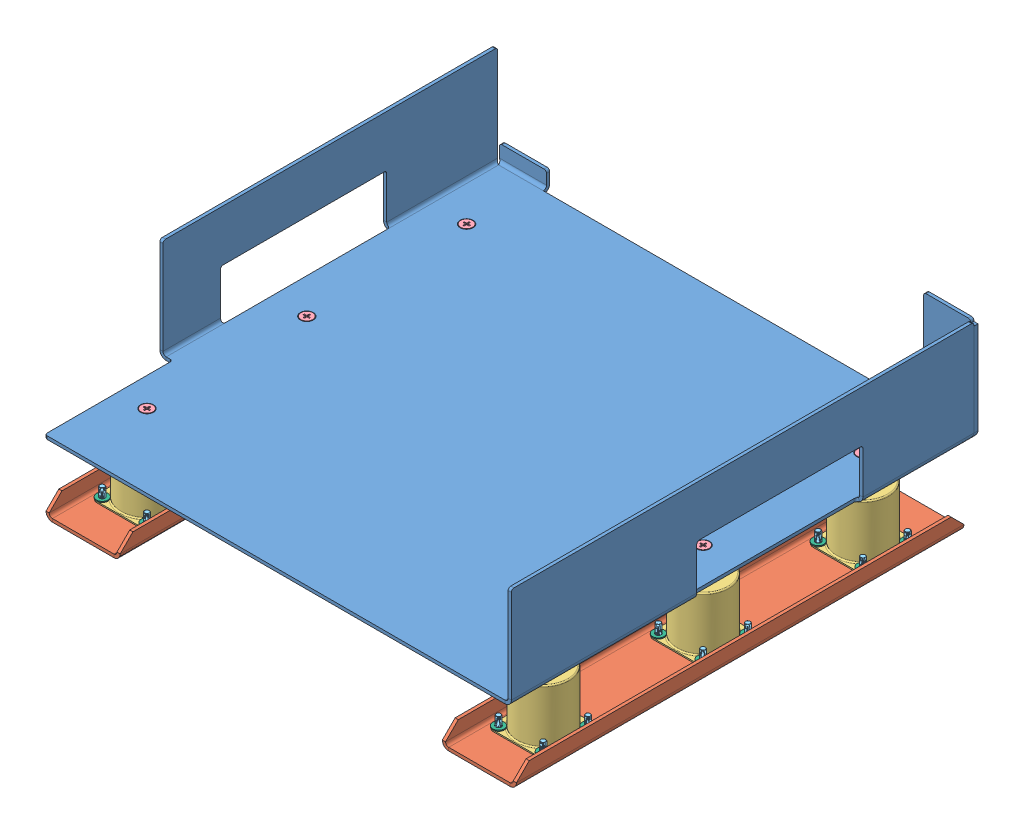
SolidWorks assembly Сборка, configuration По умолчанию. Lengths in mm.
Overall size (375.45 141.9 365.44).
63 component instances, 6 part files, 107 mates.
Components (placement in the parent):
- 1_Полка-1: 1_Полка [По умолчанию<Как обработанный>] at (-182.6691 43.1061 558.1681) size (375.45 80.44 365.44)
- 2_Основание-1: 2_Основание [По умолчанию] at (-150.1691 -18.3939 375.6681) x (0 0 -1) z (1 0 0) size (350 15 58)
- 2_Основание-2: 2_Основание [По умолчанию] at (159.8309 -18.3939 375.6681) x (0 0 1) z (-1 0 0) size (350 15 58)
- 8_Амортизатор-1: 8_Амортизатор [По умолчанию] at (-150.1691 -17.3939 500.6681) size (44 59 44)
- 8_Амортизатор-2: 8_Амортизатор [По умолчанию] at (-150.1691 -17.3939 375.6681) size (44 59 44)
- 8_Амортизатор-3: 8_Амортизатор [По умолчанию] at (159.8309 -17.3939 375.6681) size (44 59 44)
- 8_Амортизатор-4: 8_Амортизатор [По умолчанию] at (159.8309 -17.3939 250.6681) size (44 59 44)
- 8_Амортизатор-5: 8_Амортизатор [По умолчанию] at (159.8309 -17.3939 500.6681) size (44 59 44)
- 8_Амортизатор-6: 8_Амортизатор [По умолчанию] at (-150.1691 -17.3939 250.6681) size (44 59 44)
- 7_Винт_М5-1: 7_Винт_М5 [По умолчанию] at (159.8309 31.2061 250.6681) size (9.3 12.3 9.3)
- 7_Винт_М5-2: 7_Винт_М5 [По умолчанию] at (159.8309 31.2061 500.6681) size (9.3 12.3 9.3)
- 7_Винт_М5-3: 7_Винт_М5 [По умолчанию] at (159.8309 31.2061 375.6681) size (9.3 12.3 9.3)
- 7_Винт_М5-4: 7_Винт_М5 [По умолчанию] at (-150.1691 31.2061 500.6681) size (9.3 12.3 9.3)
- 7_Винт_М5-5: 7_Винт_М5 [По умолчанию] at (-150.1691 31.2061 375.6681) size (9.3 12.3 9.3)
- 7_Винт_М5-6: 7_Винт_М5 [По умолчанию] at (-150.1691 31.2061 250.6681) size (9.3 12.3 9.3)
- 6_Винт_М4-1: 6_Винт_М4 [По умолчанию] at (-132.6691 -9.2939 358.1681) x (1 0 0) z (0 0 -1) size (8.4 12.23 8.4)
- 6_Винт_М4-2: 6_Винт_М4 [По умолчанию] at (-132.6691 -9.2939 393.1681) x (1 0 0) z (0 0 -1) size (8.4 12.23 8.4)
- 6_Винт_М4-3: 6_Винт_М4 [По умолчанию] at (-132.6691 -9.2939 268.1681) x (1 0 0) z (0 0 -1) size (8.4 12.23 8.4)
- 6_Винт_М4-4: 6_Винт_М4 [По умолчанию] at (-132.6691 -9.2939 233.1681) x (1 0 0) z (0 0 -1) size (8.4 12.23 8.4)
- 6_Винт_М4-5: 6_Винт_М4 [По умолчанию] at (-167.6691 -9.2939 268.1681) x (1 0 0) z (0 0 -1) size (8.4 12.23 8.4)
- 6_Винт_М4-6: 6_Винт_М4 [По умолчанию] at (-167.6691 -9.2939 233.1681) x (1 0 0) z (0 0 -1) size (8.4 12.23 8.4)
- 6_Винт_М4-7: 6_Винт_М4 [По умолчанию] at (-167.6691 -9.2939 358.1681) x (1 0 0) z (0 0 -1) size (8.4 12.23 8.4)
- 6_Винт_М4-8: 6_Винт_М4 [По умолчанию] at (-167.6691 -9.2939 393.1681) x (1 0 0) z (0 0 -1) size (8.4 12.23 8.4)
- 6_Винт_М4-9: 6_Винт_М4 [По умолчанию] at (-132.6691 -9.2939 483.1681) x (1 0 0) z (0 0 -1) size (8.4 12.23 8.4)
- 6_Винт_М4-10: 6_Винт_М4 [По умолчанию] at (-167.6691 -9.2939 483.1681) x (1 0 0) z (0 0 -1) size (8.4 12.23 8.4)
- 6_Винт_М4-11: 6_Винт_М4 [По умолчанию] at (-132.6691 -9.2939 518.1681) x (1 0 0) z (0 0 -1) size (8.4 12.23 8.4)
- 6_Винт_М4-12: 6_Винт_М4 [По умолчанию] at (-167.6691 -9.2939 518.1681) x (1 0 0) z (0 0 -1) size (8.4 12.23 8.4)
- 6_Винт_М4-13: 6_Винт_М4 [По умолчанию] at (142.3309 -9.2939 393.1681) x (1 0 0) z (0 0 -1) size (8.4 12.23 8.4)
- 6_Винт_М4-14: 6_Винт_М4 [По умолчанию] at (177.3309 -9.2939 393.1681) x (1 0 0) z (0 0 -1) size (8.4 12.23 8.4)
- 6_Винт_М4-15: 6_Винт_М4 [По умолчанию] at (142.3309 -9.2939 358.1681) x (1 0 0) z (0 0 -1) size (8.4 12.23 8.4)
- 6_Винт_М4-16: 6_Винт_М4 [По умолчанию] at (177.3309 -9.2939 358.1681) x (1 0 0) z (0 0 -1) size (8.4 12.23 8.4)
- 6_Винт_М4-17: 6_Винт_М4 [По умолчанию] at (142.3309 -9.2939 268.1681) x (1 0 0) z (0 0 -1) size (8.4 12.23 8.4)
- 6_Винт_М4-18: 6_Винт_М4 [По умолчанию] at (177.3309 -9.2939 233.1681) x (1 0 0) z (0 0 -1) size (8.4 12.23 8.4)
- 6_Винт_М4-19: 6_Винт_М4 [По умолчанию] at (142.3309 -9.2939 233.1681) x (1 0 0) z (0 0 -1) size (8.4 12.23 8.4)
- 6_Винт_М4-20: 6_Винт_М4 [По умолчанию] at (177.3309 -9.2939 268.1681) x (1 0 0) z (0 0 -1) size (8.4 12.23 8.4)
- 6_Винт_М4-21: 6_Винт_М4 [По умолчанию] at (142.3309 -9.2939 483.1681) x (1 0 0) z (0 0 -1) size (8.4 12.23 8.4)
- 6_Винт_М4-22: 6_Винт_М4 [По умолчанию] at (142.3309 -9.2939 518.1681) x (1 0 0) z (0 0 -1) size (8.4 12.23 8.4)
- 6_Винт_М4-23: 6_Винт_М4 [По умолчанию] at (177.3309 -9.2939 518.1681) x (1 0 0) z (0 0 -1) size (8.4 12.23 8.4)
- 6_Винт_М4-24: 6_Винт_М4 [По умолчанию] at (177.3309 -9.2939 483.1681) x (1 0 0) z (0 0 -1) size (8.4 12.23 8.4)
- 5_Шайба_А4-1: 5_Шайба_А4 [По умолчанию] at (-167.6691 -17.3939 483.1681) size (9 0.8 9)
- 5_Шайба_А4-2: 5_Шайба_А4 [По умолчанию] at (-167.6691 -17.3939 518.1681) size (9 0.8 9)
- 5_Шайба_А4-3: 5_Шайба_А4 [По умолчанию] at (-132.6691 -17.3939 483.1681) size (9 0.8 9)
- 5_Шайба_А4-4: 5_Шайба_А4 [По умолчанию] at (-132.6691 -17.3939 518.1681) size (9 0.8 9)
- 5_Шайба_А4-5: 5_Шайба_А4 [По умолчанию] at (-132.6691 -17.3939 358.1681) size (9 0.8 9)
- 5_Шайба_А4-6: 5_Шайба_А4 [По умолчанию] at (-167.6691 -17.3939 358.1681) x (0.667265 0 0.74482) z (-0.74482 0 0.667265) size (9 0.8 9)
- 5_Шайба_А4-7: 5_Шайба_А4 [По умолчанию] at (-132.6691 -17.3939 393.1681) size (9 0.8 9)
- 5_Шайба_А4-8: 5_Шайба_А4 [По умолчанию] at (-167.6691 -17.3939 393.1681) x (0.975059 0 0.221947) z (-0.221947 0 0.975059) size (9 0.8 9)
- 5_Шайба_А4-9: 5_Шайба_А4 [По умолчанию] at (-167.6691 -17.3939 268.1681) size (9 0.8 9)
- 5_Шайба_А4-10: 5_Шайба_А4 [По умолчанию] at (-132.6691 -17.3939 268.1681) size (9 0.8 9)
- 5_Шайба_А4-11: 5_Шайба_А4 [По умолчанию] at (-167.6691 -17.3939 233.1681) size (9 0.8 9)
- 5_Шайба_А4-12: 5_Шайба_А4 [По умолчанию] at (-132.6691 -17.3939 233.1681) size (9 0.8 9)
- 5_Шайба_А4-13: 5_Шайба_А4 [По умолчанию] at (142.3309 -17.3939 518.1681) size (9 0.8 9)
- 5_Шайба_А4-14: 5_Шайба_А4 [По умолчанию] at (142.3309 -17.3939 483.1681) size (9 0.8 9)
- 5_Шайба_А4-15: 5_Шайба_А4 [По умолчанию] at (177.3309 -17.3939 483.1681) size (9 0.8 9)
- 5_Шайба_А4-16: 5_Шайба_А4 [По умолчанию] at (177.3309 -17.3939 518.1681) size (9 0.8 9)
- 5_Шайба_А4-17: 5_Шайба_А4 [По умолчанию] at (142.3309 -17.3939 358.1681) size (9 0.8 9)
- 5_Шайба_А4-18: 5_Шайба_А4 [По умолчанию] at (177.3309 -17.3939 393.1681) size (9 0.8 9)
- 5_Шайба_А4-19: 5_Шайба_А4 [По умолчанию] at (142.3309 -17.3939 393.1681) size (9 0.8 9)
- 5_Шайба_А4-20: 5_Шайба_А4 [По умолчанию] at (177.3309 -17.3939 358.1681) size (9 0.8 9)
- 5_Шайба_А4-21: 5_Шайба_А4 [По умолчанию] at (142.3309 -17.3939 268.1681) size (9 0.8 9)
- 5_Шайба_А4-22: 5_Шайба_А4 [По умолчанию] at (142.3309 -17.3939 233.1681) size (9 0.8 9)
- 5_Шайба_А4-23: 5_Шайба_А4 [По умолчанию] at (177.3309 -17.3939 233.1681) size (9 0.8 9)
- 5_Шайба_А4-24: 5_Шайба_А4 [По умолчанию] at (177.3309 -17.3939 268.1681) size (9 0.8 9)
Mates (geometry in assembly coordinates):
- Концентричный1: concentric aligned: circle of 1_Полка-1; circle of 8_Амортизатор-6
- Совпадение2: coincident anti-aligned: plane of 1_Полка-1 through (-182.6691 40.6061 558.1681) normal (0 -1 0); plane of 8_Амортизатор-6 through (-150.1691 40.6061 250.6681) normal (0 1 0)
- Совпадение3: coincident aligned: cone of 1_Полка-1 through (-150.1691 40.7561 250.6681) axis (0 -1 0); cone of 7_Винт_М5-6 through (-150.1691 42.6561 250.6681) axis (0 -1 0)
- Концентричный2: concentric aligned: circle of 1_Полка-1; circle of 8_Амортизатор-2
- Совпадение4: coincident anti-aligned: plane of 1_Полка-1 through (-182.6691 40.6061 558.1681) normal (0 -1 0); plane of 8_Амортизатор-2 through (-150.1691 40.6061 375.6681) normal (0 1 0)
- Концентричный3: concentric aligned: circle of 1_Полка-1; circle of 8_Амортизатор-1
- Совпадение5: coincident anti-aligned: plane of 1_Полка-1 through (-182.6691 40.6061 558.1681) normal (0 -1 0); plane of 8_Амортизатор-1 through (-150.1691 40.6061 500.6681) normal (0 1 0)
- Концентричный4: concentric aligned: circle of 1_Полка-1; circle of 8_Амортизатор-4
- Совпадение6: coincident anti-aligned: plane of 1_Полка-1 through (-182.6691 40.6061 558.1681) normal (0 -1 0); plane of 8_Амортизатор-4 through (159.8309 40.6061 250.6681) normal (0 1 0)
- Концентричный5: concentric aligned: circle of 1_Полка-1; circle of 8_Амортизатор-3
- Совпадение7: coincident anti-aligned: plane of 1_Полка-1 through (-182.6691 40.6061 558.1681) normal (0 -1 0); plane of 8_Амортизатор-3 through (159.8309 40.6061 375.6681) normal (0 1 0)
- Концентричный6: concentric aligned: circle of 1_Полка-1; circle of 8_Амортизатор-5
- Совпадение8: coincident anti-aligned: plane of 1_Полка-1 through (-182.6691 40.6061 558.1681) normal (0 -1 0); plane of 8_Амортизатор-5 through (159.8309 40.6061 500.6681) normal (0 1 0)
- Совпадение9: coincident aligned: cone of 1_Полка-1 through (-150.1691 40.7561 375.6681) axis (0 -1 0); cone of 7_Винт_М5-5 through (-150.1691 42.6561 375.6681) axis (0 -1 0)
- Совпадение10: coincident aligned: cone of 1_Полка-1 through (-150.1691 40.7561 500.6681) axis (0 -1 0); cone of 7_Винт_М5-4 through (-150.1691 42.6561 500.6681) axis (0 -1 0)
- Совпадение11: coincident aligned: cone of 1_Полка-1 through (159.8309 40.7561 500.6681) axis (0 -1 0); cone of 7_Винт_М5-2 through (159.8309 42.6561 500.6681) axis (0 -1 0)
- Совпадение12: coincident aligned: cone of 1_Полка-1 through (159.8309 40.7561 375.6681) axis (0 -1 0); cone of 7_Винт_М5-3 through (159.8309 42.6561 375.6681) axis (0 -1 0)
- Совпадение14: coincident aligned: cone of 1_Полка-1 through (159.8309 40.7561 250.6681) axis (0 -1 0); cone of 7_Винт_М5-1 through (159.8309 42.6561 250.6681) axis (0 -1 0)
- Концентричный11: concentric aligned: circle of 2_Основание-1; circle of 8_Амортизатор-6
- Концентричный12: concentric aligned: circle of 2_Основание-1; circle of 8_Амортизатор-6
- Концентричный13: concentric aligned: circle of 2_Основание-1; circle of 8_Амортизатор-2
- Концентричный14: concentric anti-aligned: cylinder of 2_Основание-1; cylinder of 8_Амортизатор-2 through (-132.6691 24.8061 393.1681) axis (0 -1 0) radius 2
- Концентричный15: concentric anti-aligned: circle of 2_Основание-1; cylinder of 8_Амортизатор-1 through (-167.6691 24.8061 483.1681) axis (0 -1 0) radius 2
- Концентричный16: concentric aligned: circle of 2_Основание-1; circle of 8_Амортизатор-1
- Совпадение15: coincident anti-aligned: plane of 2_Основание-1 through (-150.1691 -18.3939 375.6681) normal (0 1 0); plane of 8_Амортизатор-1 through (-150.1691 -18.3939 500.6681) normal (0 -1 0)
- Совпадение16: coincident aligned: cone of 2_Основание-1 through (-167.6691 -20.8939 518.1681) axis (0 1 0); cone of 6_Винт_М4-12 through (-167.6691 -20.7939 518.1681) axis (0 1 0)
- Совпадение17: coincident aligned: cone of 2_Основание-1 through (-132.6691 -20.8939 518.1681) axis (0 1 0); cone of 6_Винт_М4-11 through (-132.6691 -20.7939 518.1681) axis (0 1 0)
- Совпадение18: coincident anti-aligned: cone of 2_Основание-1 through (-167.6691 -20.8939 483.1681) axis (0 1 0); circle of 6_Винт_М4-10
- Совпадение19: coincident anti-aligned: cone of 2_Основание-1 through (-132.6691 -20.8939 483.1681) axis (0 1 0); circle of 6_Винт_М4-9
- Совпадение20: coincident aligned: cone of 2_Основание-1 through (-167.6691 -20.8939 393.1681) axis (0 1 0); cone of 6_Винт_М4-8 through (-167.6691 -20.7939 393.1681) axis (0 1 0)
- Совпадение21: coincident aligned: cone of 2_Основание-1 through (-132.6691 -20.8939 358.1681) axis (0 1 0); cone of 6_Винт_М4-1 through (-132.6691 -20.7939 358.1681) axis (0 1 0)
- Совпадение22: coincident aligned: cone of 2_Основание-1 through (-167.6691 -20.8939 358.1681) axis (0 1 0); cone of 6_Винт_М4-7 through (-167.6691 -20.7939 358.1681) axis (0 1 0)
- Совпадение23: coincident aligned: cone of 2_Основание-1 through (-132.6691 -20.8939 393.1681) axis (0 1 0); cone of 6_Винт_М4-2 through (-132.6691 -20.7939 393.1681) axis (0 1 0)
- Совпадение24: coincident aligned: cone of 2_Основание-1 through (-167.6691 -20.8939 268.1681) axis (0 1 0); cone of 6_Винт_М4-5 through (-167.6691 -20.7939 268.1681) axis (0 1 0)
- Совпадение25: coincident aligned: cone of 2_Основание-1 through (-167.6691 -20.8939 233.1681) axis (0 1 0); cone of 6_Винт_М4-6 through (-167.6691 -20.7939 233.1681) axis (0 1 0)
- Совпадение26: coincident aligned: cone of 2_Основание-1 through (-132.6691 -20.8939 233.1681) axis (0 1 0); cone of 6_Винт_М4-4 through (-132.6691 -20.7939 233.1681) axis (0 1 0)
- Совпадение27: coincident aligned: cone of 2_Основание-1 through (-132.6691 -20.8939 268.1681) axis (0 1 0); cone of 6_Винт_М4-3 through (-132.6691 -20.7939 268.1681) axis (0 1 0)
- Концентричный17: concentric anti-aligned: circle of 2_Основание-2; cylinder of 8_Амортизатор-5 through (142.3309 24.8061 483.1681) axis (0 -1 0) radius 2
- Концентричный18: concentric anti-aligned: circle of 2_Основание-2; cylinder of 8_Амортизатор-5 through (177.3309 24.8061 518.1681) axis (0 -1 0) radius 2
- Концентричный19: concentric anti-aligned: circle of 2_Основание-2; cylinder of 8_Амортизатор-3 through (142.3309 24.8061 393.1681) axis (0 -1 0) radius 2
- Концентричный20: concentric aligned: circle of 2_Основание-2; circle of 8_Амортизатор-3
- Концентричный21: concentric anti-aligned: circle of 2_Основание-2; cylinder of 8_Амортизатор-4 through (142.3309 24.8061 268.1681) axis (0 -1 0) radius 2
- Концентричный22: concentric anti-aligned: circle of 2_Основание-2; cylinder of 8_Амортизатор-4 through (177.3309 24.8061 233.1681) axis (0 -1 0) radius 2
- Совпадение28: coincident anti-aligned: plane of 2_Основание-2 through (159.8309 -18.3939 375.6681) normal (0 1 0); plane of 8_Амортизатор-5 through (159.8309 -18.3939 500.6681) normal (0 -1 0)
- Совпадение29: coincident aligned: cone of 2_Основание-2 through (142.3309 -20.8939 518.1681) axis (0 1 0); cone of 6_Винт_М4-22 through (142.3309 -20.7939 518.1681) axis (0 1 0)
- Совпадение30: coincident aligned: cone of 2_Основание-2 through (177.3309 -20.8939 518.1681) axis (0 1 0); cone of 6_Винт_М4-23 through (177.3309 -20.7939 518.1681) axis (0 1 0)
- Совпадение31: coincident aligned: cone of 2_Основание-2 through (142.3309 -20.8939 483.1681) axis (0 1 0); cone of 6_Винт_М4-21 through (142.3309 -20.7939 483.1681) axis (0 1 0)
- Совпадение32: coincident aligned: cone of 2_Основание-2 through (177.3309 -20.8939 483.1681) axis (0 1 0); cone of 6_Винт_М4-24 through (177.3309 -20.7939 483.1681) axis (0 1 0)
- Совпадение33: coincident aligned: cone of 2_Основание-2 through (142.3309 -20.8939 393.1681) axis (0 1 0); cone of 6_Винт_М4-13 through (142.3309 -20.7939 393.1681) axis (0 1 0)
- Совпадение34: coincident aligned: cone of 2_Основание-2 through (177.3309 -20.8939 393.1681) axis (0 1 0); cone of 6_Винт_М4-14 through (177.3309 -20.7939 393.1681) axis (0 1 0)
- Совпадение35: coincident aligned: cone of 2_Основание-2 through (142.3309 -20.8939 358.1681) axis (0 1 0); cone of 6_Винт_М4-15 through (142.3309 -20.7939 358.1681) axis (0 1 0)
- Совпадение36: coincident aligned: cone of 2_Основание-2 through (177.3309 -20.8939 358.1681) axis (0 1 0); cone of 6_Винт_М4-16 through (177.3309 -20.7939 358.1681) axis (0 1 0)
- Совпадение37: coincident aligned: cone of 2_Основание-2 through (142.3309 -20.8939 268.1681) axis (0 1 0); cone of 6_Винт_М4-17 through (142.3309 -20.7939 268.1681) axis (0 1 0)
- Совпадение38: coincident aligned: cone of 2_Основание-2 through (177.3309 -20.8939 233.1681) axis (0 1 0); cone of 6_Винт_М4-18 through (177.3309 -20.7939 233.1681) axis (0 1 0)
- Совпадение39: coincident aligned: cone of 2_Основание-2 through (177.3309 -20.8939 268.1681) axis (0 1 0); cone of 6_Винт_М4-20 through (177.3309 -20.7939 268.1681) axis (0 1 0)
- Совпадение40: coincident aligned: cone of 2_Основание-2 through (142.3309 -20.8939 233.1681) axis (0 1 0); cone of 6_Винт_М4-19 through (142.3309 -20.7939 233.1681) axis (0 1 0)
- Совпадение43: coincident anti-aligned: plane of 8_Амортизатор-1 through (-150.1691 -17.3939 500.6681) normal (0 1 0); plane of 5_Шайба_А4-2 through (-167.6691 -17.3939 518.1681) normal (0 -1 0)
- Концентричный24: concentric aligned: circle of 8_Амортизатор-1; circle of 5_Шайба_А4-2
- Совпадение44: coincident anti-aligned: plane of 8_Амортизатор-1 through (-150.1691 -17.3939 500.6681) normal (0 1 0); plane of 5_Шайба_А4-4 through (-132.6691 -17.3939 518.1681) normal (0 -1 0)
- Концентричный25: concentric aligned: circle of 8_Амортизатор-1; circle of 5_Шайба_А4-4
- Совпадение45: coincident anti-aligned: plane of 8_Амортизатор-1 through (-150.1691 -17.3939 500.6681) normal (0 1 0); plane of 5_Шайба_А4-1 through (-167.6691 -17.3939 483.1681) normal (0 -1 0)
- Концентричный26: concentric aligned: circle of 8_Амортизатор-1; circle of 5_Шайба_А4-1
- Совпадение46: coincident aligned: plane of 8_Амортизатор-1 through (-150.1691 -17.3939 500.6681) normal (0 1 0); circle of 5_Шайба_А4-3
- Концентричный27: concentric aligned: circle of 8_Амортизатор-1; circle of 5_Шайба_А4-3
- Концентричный28: concentric aligned: circle of 8_Амортизатор-2; circle of 5_Шайба_А4-7
- Совпадение47: coincident anti-aligned: plane of 8_Амортизатор-2 through (-150.1691 -17.3939 375.6681) normal (0 1 0); plane of 5_Шайба_А4-7 through (-132.6691 -17.3939 393.1681) normal (0 -1 0)
- Концентричный29: concentric aligned: circle of 8_Амортизатор-2; circle of 5_Шайба_А4-8
- Совпадение49: coincident anti-aligned: plane of 8_Амортизатор-2 through (-150.1691 -17.3939 375.6681) normal (0 1 0); plane of 5_Шайба_А4-8 through (-167.6691 -17.3939 393.1681) normal (0 -1 0)
- Концентричный30: concentric aligned: circle of 8_Амортизатор-2; circle of 5_Шайба_А4-6
- Совпадение51: coincident anti-aligned: plane of 8_Амортизатор-2 through (-150.1691 -17.3939 375.6681) normal (0 1 0); plane of 5_Шайба_А4-6 through (-167.6691 -17.3939 358.1681) normal (0 -1 0)
- Концентричный31: concentric: circle of 8_Амортизатор-2; circle of 5_Шайба_А4-5
- Совпадение54: coincident anti-aligned: plane of 8_Амортизатор-2 through (-150.1691 -17.3939 375.6681) normal (0 1 0); plane of 5_Шайба_А4-5 through (-132.6691 -17.3939 358.1681) normal (0 -1 0)
- Концентричный32: concentric: circle of 8_Амортизатор-6; circle of 5_Шайба_А4-9
- Совпадение55: coincident anti-aligned: plane of 8_Амортизатор-6 through (-150.1691 -17.3939 250.6681) normal (0 1 0); plane of 5_Шайба_А4-9 through (-167.6691 -17.3939 268.1681) normal (0 -1 0)
- Совпадение56: coincident: plane of 8_Амортизатор-6 through (-150.1691 -17.3939 250.6681) normal (0 1 0); plane of 5_Шайба_А4-11 through (-167.6691 -17.3939 233.1681) normal (0 -1 0)
- Совпадение57: coincident: plane of 8_Амортизатор-6 through (-150.1691 -17.3939 250.6681) normal (0 1 0); plane of 5_Шайба_А4-10 through (-132.6691 -17.3939 268.1681) normal (0 -1 0)
- Совпадение58: coincident: plane of 8_Амортизатор-6 through (-150.1691 -17.3939 250.6681) normal (0 1 0); circle of 5_Шайба_А4-12
- Концентричный33: concentric aligned: circle of 8_Амортизатор-6; circle of 5_Шайба_А4-12
- Концентричный34: concentric aligned: circle of 8_Амортизатор-6; circle of 5_Шайба_А4-11
- Концентричный35: concentric aligned: circle of 8_Амортизатор-6; circle of 5_Шайба_А4-10
- Совпадение59: coincident aligned: plane of 5_Шайба_А4-23 through (177.3309 -17.3939 233.1681) normal (0 -1 0); plane of 5_Шайба_А4-24 through (177.3309 -17.3939 268.1681) normal (0 -1 0)
- Совпадение60: coincident aligned: plane of 5_Шайба_А4-21 through (142.3309 -17.3939 268.1681) normal (0 -1 0); plane of 5_Шайба_А4-23 through (177.3309 -17.3939 233.1681) normal (0 -1 0)
- Совпадение61: coincident aligned: plane of 5_Шайба_А4-22 through (142.3309 -17.3939 233.1681) normal (0 -1 0); plane of 5_Шайба_А4-23 through (177.3309 -17.3939 233.1681) normal (0 -1 0)
- Совпадение62: coincident anti-aligned: plane of 8_Амортизатор-4 through (159.8309 -17.3939 250.6681) normal (0 1 0); plane of 5_Шайба_А4-23 through (177.3309 -17.3939 233.1681) normal (0 -1 0)
- Совпадение63: coincident anti-aligned: plane of 8_Амортизатор-4 through (159.8309 -17.3939 250.6681) normal (0 1 0); plane of 5_Шайба_А4-22 through (142.3309 -17.3939 233.1681) normal (0 -1 0)
- Совпадение64: coincident anti-aligned: plane of 8_Амортизатор-4 through (159.8309 -17.3939 250.6681) normal (0 1 0); plane of 5_Шайба_А4-21 through (142.3309 -17.3939 268.1681) normal (0 -1 0)
- Совпадение65: coincident anti-aligned: plane of 8_Амортизатор-4 through (159.8309 -17.3939 250.6681) normal (0 1 0); plane of 5_Шайба_А4-24 through (177.3309 -17.3939 268.1681) normal (0 -1 0)
- Концентричный36: concentric aligned: circle of 8_Амортизатор-4; circle of 5_Шайба_А4-24
- Концентричный37: concentric aligned: circle of 8_Амортизатор-4; circle of 5_Шайба_А4-21
- Концентричный38: concentric aligned: circle of 8_Амортизатор-4; circle of 5_Шайба_А4-23
- Концентричный39: concentric aligned: circle of 8_Амортизатор-4; circle of 5_Шайба_А4-22
- Совпадение66: coincident: plane of 8_Амортизатор-3 through (159.8309 -17.3939 375.6681) normal (0 1 0); plane of 5_Шайба_А4-18 through (177.3309 -17.3939 393.1681) normal (0 -1 0)
- Концентричный40: concentric aligned: circle of 8_Амортизатор-3; circle of 5_Шайба_А4-18
- Совпадение67: coincident: plane of 8_Амортизатор-3 through (159.8309 -17.3939 375.6681) normal (0 1 0); plane of 5_Шайба_А4-20 through (177.3309 -17.3939 358.1681) normal (0 -1 0)
- Концентричный41: concentric aligned: circle of 8_Амортизатор-3; circle of 5_Шайба_А4-20
- Совпадение68: coincident: plane of 8_Амортизатор-3 through (159.8309 -17.3939 375.6681) normal (0 1 0); plane of 5_Шайба_А4-17 through (142.3309 -17.3939 358.1681) normal (0 -1 0)
- Концентричный42: concentric aligned: circle of 8_Амортизатор-3; circle of 5_Шайба_А4-17
- Совпадение69: coincident: plane of 8_Амортизатор-3 through (159.8309 -17.3939 375.6681) normal (0 1 0); plane of 5_Шайба_А4-19 through (142.3309 -17.3939 393.1681) normal (0 -1 0)
- Концентричный43: concentric aligned: circle of 8_Амортизатор-3; circle of 5_Шайба_А4-19
- Совпадение70: coincident: plane of 8_Амортизатор-5 through (159.8309 -17.3939 500.6681) normal (0 1 0); plane of 5_Шайба_А4-15 through (177.3309 -17.3939 483.1681) normal (0 -1 0)
- Концентричный44: concentric aligned: circle of 8_Амортизатор-5; circle of 5_Шайба_А4-15
- Совпадение71: coincident: plane of 8_Амортизатор-5 through (159.8309 -17.3939 500.6681) normal (0 1 0); plane of 5_Шайба_А4-14 through (142.3309 -17.3939 483.1681) normal (0 -1 0)
- Концентричный45: concentric anti-aligned: circle of 8_Амортизатор-5; cylinder of 5_Шайба_А4-14 through (142.3309 -16.5939 483.1681) axis (0 -1 0) radius 2.15
- Совпадение72: coincident: plane of 8_Амортизатор-5 through (159.8309 -17.3939 500.6681) normal (0 1 0); plane of 5_Шайба_А4-13 through (142.3309 -17.3939 518.1681) normal (0 -1 0)
- Концентричный46: concentric aligned: circle of 8_Амортизатор-5; circle of 5_Шайба_А4-13
- Совпадение73: coincident: plane of 8_Амортизатор-5 through (159.8309 -17.3939 500.6681) normal (0 1 0); plane of 5_Шайба_А4-16 through (177.3309 -17.3939 518.1681) normal (0 -1 0)
- Концентричный47: concentric aligned: circle of 8_Амортизатор-5; circle of 5_Шайба_А4-16
